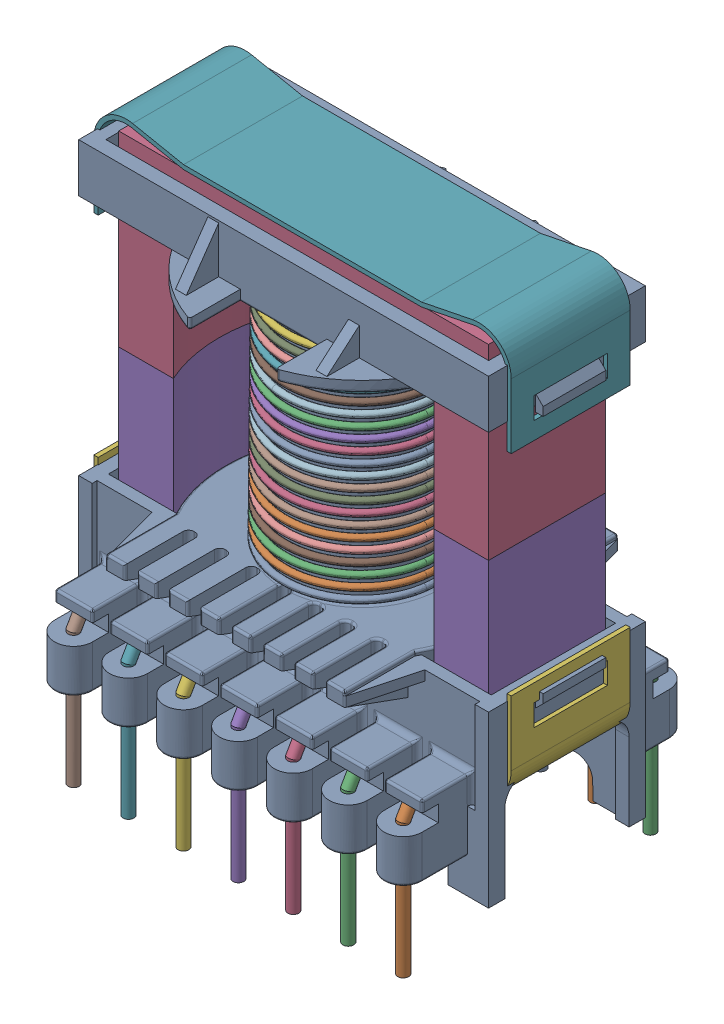
SolidWorks assembly ETD_34_Vertical, configuration Default. Lengths in mm.
Overall size (39.3 49.7 26.36).
21 component instances, 5 part files, 0 mates.
Components (placement in the parent):
- User_Library-ETD34-17-11_Vertical_Bobbin_Part_No._FD9640-1: User_Library-ETD34-17-11_Vertical_Bobbin_Part_No._FD9640 [Default] at (-19.65 26.6 -12.65) x (-1 0 0) z (0 0 1) size (39.3 49.7 26.36)
  - User_Library-ETD34-17-11_Vertical_Bobbin_Part_No._FD9640_FD9640-1: User_Library-ETD34-17-11_Vertical_Bobbin_Part_No._FD9640_FD9640 [Default] at origin size (39.3 42.6 26.36)
  - User_Library-ETD34-17-11_Vertical_Bobbin_Part_No._FD9640_1MM_RND_PIN-1: User_Library-ETD34-17-11_Vertical_Bobbin_Part_No._FD9640_1MM_RND_PIN [Default] at origin size (1 13.75 1.63)
  - User_Library-ETD34-17-11_Vertical_Bobbin_Part_No._FD9640_1MM_RND_PIN-2: User_Library-ETD34-17-11_Vertical_Bobbin_Part_No._FD9640_1MM_RND_PIN [Default] at (5.08 0 0) size (1 13.75 1.63)
  - User_Library-ETD34-17-11_Vertical_Bobbin_Part_No._FD9640_1MM_RND_PIN-3: User_Library-ETD34-17-11_Vertical_Bobbin_Part_No._FD9640_1MM_RND_PIN [Default] at (10.16 0 0) size (1 13.75 1.63)
  - User_Library-ETD34-17-11_Vertical_Bobbin_Part_No._FD9640_1MM_RND_PIN-4: User_Library-ETD34-17-11_Vertical_Bobbin_Part_No._FD9640_1MM_RND_PIN [Default] at (15.24 0 0) size (1 13.75 1.63)
  - User_Library-ETD34-17-11_Vertical_Bobbin_Part_No._FD9640_1MM_RND_PIN-5: User_Library-ETD34-17-11_Vertical_Bobbin_Part_No._FD9640_1MM_RND_PIN [Default] at (20.32 0 0) size (1 13.75 1.63)
  - User_Library-ETD34-17-11_Vertical_Bobbin_Part_No._FD9640_1MM_RND_PIN-6: User_Library-ETD34-17-11_Vertical_Bobbin_Part_No._FD9640_1MM_RND_PIN [Default] at (25.4 0 0) size (1 13.75 1.63)
  - User_Library-ETD34-17-11_Vertical_Bobbin_Part_No._FD9640_1MM_RND_PIN-7: User_Library-ETD34-17-11_Vertical_Bobbin_Part_No._FD9640_1MM_RND_PIN [Default] at (30.48 0 0) size (1 13.75 1.63)
  - User_Library-ETD34-17-11_Vertical_Bobbin_Part_No._FD9640_1MM_RND_PIN-8: User_Library-ETD34-17-11_Vertical_Bobbin_Part_No._FD9640_1MM_RND_PIN [Default] x (-1 0 0) z (0 0 -1) size (1 13.75 1.63)
  - User_Library-ETD34-17-11_Vertical_Bobbin_Part_No._FD9640_1MM_RND_PIN-9: User_Library-ETD34-17-11_Vertical_Bobbin_Part_No._FD9640_1MM_RND_PIN [Default] at (-5.08 0 0) x (-1 0 0) z (0 0 -1) size (1 13.75 1.63)
  - User_Library-ETD34-17-11_Vertical_Bobbin_Part_No._FD9640_1MM_RND_PIN-10: User_Library-ETD34-17-11_Vertical_Bobbin_Part_No._FD9640_1MM_RND_PIN [Default] at (-10.16 0 0) x (-1 0 0) z (0 0 -1) size (1 13.75 1.63)
  - User_Library-ETD34-17-11_Vertical_Bobbin_Part_No._FD9640_1MM_RND_PIN-11: User_Library-ETD34-17-11_Vertical_Bobbin_Part_No._FD9640_1MM_RND_PIN [Default] at (-15.24 0 0) x (-1 0 0) z (0 0 -1) size (1 13.75 1.63)
  - User_Library-ETD34-17-11_Vertical_Bobbin_Part_No._FD9640_1MM_RND_PIN-12: User_Library-ETD34-17-11_Vertical_Bobbin_Part_No._FD9640_1MM_RND_PIN [Default] at (-20.32 0 0) x (-1 0 0) z (0 0 -1) size (1 13.75 1.63)
  - User_Library-ETD34-17-11_Vertical_Bobbin_Part_No._FD9640_1MM_RND_PIN-13: User_Library-ETD34-17-11_Vertical_Bobbin_Part_No._FD9640_1MM_RND_PIN [Default] at (-25.4 0 0) x (-1 0 0) z (0 0 -1) size (1 13.75 1.63)
  - User_Library-ETD34-17-11_Vertical_Bobbin_Part_No._FD9640_1MM_RND_PIN-14: User_Library-ETD34-17-11_Vertical_Bobbin_Part_No._FD9640_1MM_RND_PIN [Default] at (-30.48 0 0) x (-1 0 0) z (0 0 -1) size (1 13.75 1.63)
  - User_Library-ETD34-17-11_Vertical_Bobbin_Part_No._FD9640_ETD34_CORE-1: User_Library-ETD34-17-11_Vertical_Bobbin_Part_No._FD9640_ETD34_CORE [Default] at (0 -16.7 0) size (34.2 17.3 10.8)
  - User_Library-ETD34-17-11_Vertical_Bobbin_Part_No._FD9640_ETD34_CORE-2: User_Library-ETD34-17-11_Vertical_Bobbin_Part_No._FD9640_ETD34_CORE [Default] at (0 17.9 0) x (-1 0 0) z (0 0 1) size (34.2 17.3 10.8)
  - User_Library-ETD34-17-11_Vertical_Bobbin_Part_No._FD9640_ETD34_CORE_CLIP-1: User_Library-ETD34-17-11_Vertical_Bobbin_Part_No._FD9640_ETD34_CORE_CLIP [Default] at (0 10.3 -5.5) x (0 -1 0) z (-1 0 0) size (9 11 38.6)
  - User_Library-ETD34-17-11_Vertical_Bobbin_Part_No._FD9640_ETD34_CORE_CLIP-2: User_Library-ETD34-17-11_Vertical_Bobbin_Part_No._FD9640_ETD34_CORE_CLIP [Default] at (0 -9.1 5.5) x (0 1 0) z (-1 0 0) size (9 11 38.6)
  - User_Library-ETD34-17-11_Vertical_Bobbin_Part_No._FD9640_ETD34_WINDING-1: User_Library-ETD34-17-11_Vertical_Bobbin_Part_No._FD9640_ETD34_WINDING [Default] at (0.2458 10.0424 -0.0108) x (-0.015539 -0.999863 0.005636) z (0.990175 -0.016171 -0.138898) size (20.6 14.6 14.6)
